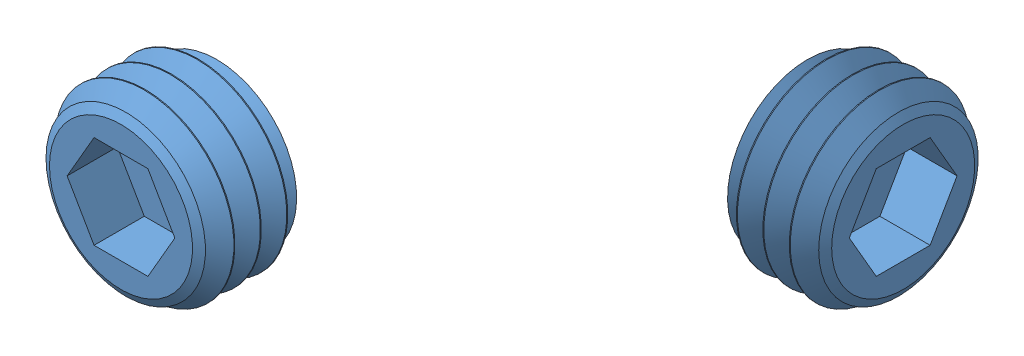
SolidWorks assembly KFL08_Seperate, configuration Varsayılan. Lengths in mm.
Overall size (6.7 2.5 6.7).
4 component instances, 3 part files, 10 mates.
Components (placement in the parent):
- FLANGE-1: FLANGE [Default] at origin (suppressed, hidden)
- BEARING-1: BEARING [Default] at (0 4 0) x (1 0 0) z (0 -1 0) (suppressed, hidden)
- socket set screw cone point_am-1: socket set screw cone point_am [B18.3.6M - M2.5 x 0.45 x 2 Hex Socket Cone Pt. SS --S] at (0 9.425 5.45) x (0 0 -1) z (1 0 0) size (2 2.5 2.5)
- socket set screw cone point_am-2: socket set screw cone point_am [B18.3.6M - M2.5 x 0.45 x 2 Hex Socket Cone Pt. SS --S] at (5.45 9.425 0) x (-1 0 0) z (0 0 -1) size (2 2.5 2.5)
Mates (geometry in assembly coordinates):
- Coincident1: coincident: plane of FLANGE-1 through (0 0.5 0) normal (0 -1 0); plane of BEARING-1 through (0 0.5 9.6) normal (0 -1 0)
- Coincident2: coordinate: point of FLANGE-1; point of assembly
- Coincident3: coincident: plane of FLANGE-1 through (0 0 0) normal (1 0 0); plane of BEARING-1
- Concentric2: concentric: cylinder of BEARING-1 through (0 9.425 5.45) axis (0 0 1) radius 1.25; cylinder of socket set screw cone point_am-1 through (0 9.425 18.15) axis (0 0 1) radius 1.25
- Tangent1: tangent: cylinder of BEARING-1 through (0 0.5 0) axis (0 -1 0) radius 5.45; plane of socket set screw cone point_am-1 through (0 9.425 5.45) normal (0 0 1)
- Concentric3: concentric: cylinder of BEARING-1 through (5.45 9.425 0) axis (1 0 0) radius 1.25; cylinder of socket set screw cone point_am-2 through (18.15 9.425 0) axis (1 0 0) radius 1.25
- Tangent3: tangent: cylinder of BEARING-1 through (0 0.5 0) axis (0 -1 0) radius 5.45; plane of socket set screw cone point_am-2 through (5.45 9.425 0) normal (1 0 0)
- Parallel1: parallel: plane of socket set screw cone point_am-1 through (0 9.425 5.45) normal (0 1 0); plane of assembly through (0 0 0) normal (0 1 0)
- Parallel2: parallel: plane of socket set screw cone point_am-2 through (5.45 9.425 0) normal (0 1 0); plane of assembly through (0 0 0) normal (0 1 0)
- Coincident4: coincident: line of FLANGE-1 through (9.35 0 -0.425) axis (0 0 1); line of BEARING-1 through (10.25 0 11.05) axis (0 0 -1)
